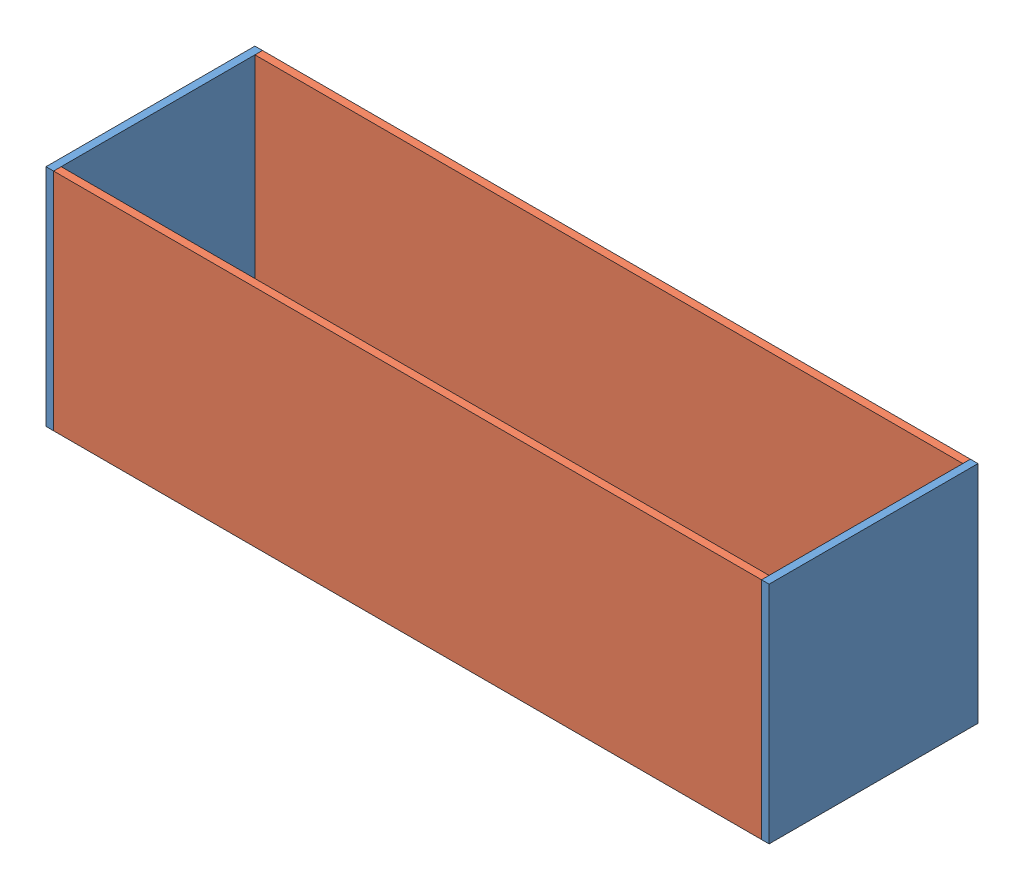
SolidWorks assembly drainageresovoir, configuration Default. Lengths in mm.
Overall size (285.75 88.9 82.55).
8 component instances, 5 part files, 12 mates.
Components (placement in the parent):
- bottom-1: bottom [Default] at (-164.1543 5.6353 -30.8572) (suppressed, hidden)
- side-1: side [Default] at (115.6013 94.5353 48.6956) x (0 0 -1) z (1 0 0) (suppressed, hidden)
- side-2: side [Default] at (-164.1543 94.5353 -33.8544) x (0 0 1) z (-1 0 0) (suppressed, hidden)
- front-1: front [Default] at (123.921 88.414 48.6956) x (0 0 -1) z (1 0 0) size (82.55 88.9 3)
- front-2: front [Default] at (-155.8346 88.414 -33.8544) x (0 0 1) z (-1 0 0) size (82.55 88.9 3)
- drsides-1: drsides [Default] at (123.921 88.414 48.6956) x (0 0 -1) z (1 0 0) size (3 88.9 279.76)
- drsides-2: drsides [Default] at (123.921 88.414 -30.8572) x (0 0 -1) z (1 0 0) size (3 88.9 279.76)
- drbottom-1: drbottom [Default] at (-155.8346 -0.486 -30.8572) size (279.76 3 76.56)
Mates (geometry in assembly coordinates):
- Coincident16: coincident aligned: plane of front-1 through (126.9182 88.414 48.6956) normal (0 1 0); plane of drsides-1 through (123.921 88.414 45.6984) normal (0 1 0)
- Coincident18: coincident aligned: plane of front-2 through (-158.8318 88.414 48.6956) normal (0 0 1); plane of drsides-1 through (123.921 88.414 48.6956) normal (0 0 1)
- Coincident19: coincident anti-aligned: plane of front-2 through (-155.8346 88.414 -33.8544) normal (1 0 0); plane of drsides-1 through (-155.8346 88.414 45.6984) normal (-1 0 0)
- Coincident20: coincident anti-aligned: plane of front-1 through (123.921 88.414 48.6956) normal (-1 0 0); plane of drsides-1 through (123.921 88.414 45.6984) normal (1 0 0)
- Coincident21: coincident aligned: plane of front-1 through (126.9182 88.414 48.6956) normal (0 0 1); plane of drsides-1 through (123.921 88.414 48.6956) normal (0 0 1)
- Coincident22: coincident aligned: plane of front-2 through (-158.8318 88.414 -33.8544) normal (0 1 0); plane of drsides-1 through (123.921 88.414 45.6984) normal (0 1 0)
- Coincident23: coincident aligned: plane of front-1 through (126.9182 88.414 -33.8544) normal (0 0 -1); plane of drsides-2 through (123.921 88.414 -33.8544) normal (0 0 -1)
- Coincident24: coincident anti-aligned: plane of front-1 through (123.921 88.414 48.6956) normal (-1 0 0); plane of drsides-2 through (123.921 88.414 -33.8544) normal (1 0 0)
- Coincident25: coincident aligned: plane of front-1 through (126.9182 -0.486 48.6956) normal (0 -1 0); plane of drsides-2 through (123.921 -0.486 -33.8544) normal (0 -1 0)
- Coincident26: coincident aligned: plane of front-2 through (-158.8318 -0.486 -33.8544) normal (0 -1 0); plane of drbottom-1 through (-155.8346 -0.486 -30.8572) normal (0 -1 0)
- Coincident27: coincident anti-aligned: plane of front-2 through (-155.8346 88.414 -33.8544) normal (1 0 0); plane of drbottom-1 through (-155.8346 2.5112 -30.8572) normal (-1 0 0)
- Coincident28: coincident anti-aligned: plane of drsides-2 through (123.921 88.414 -30.8572) normal (0 0 1); plane of drbottom-1 through (-155.8346 2.5112 -30.8572) normal (0 0 -1)
